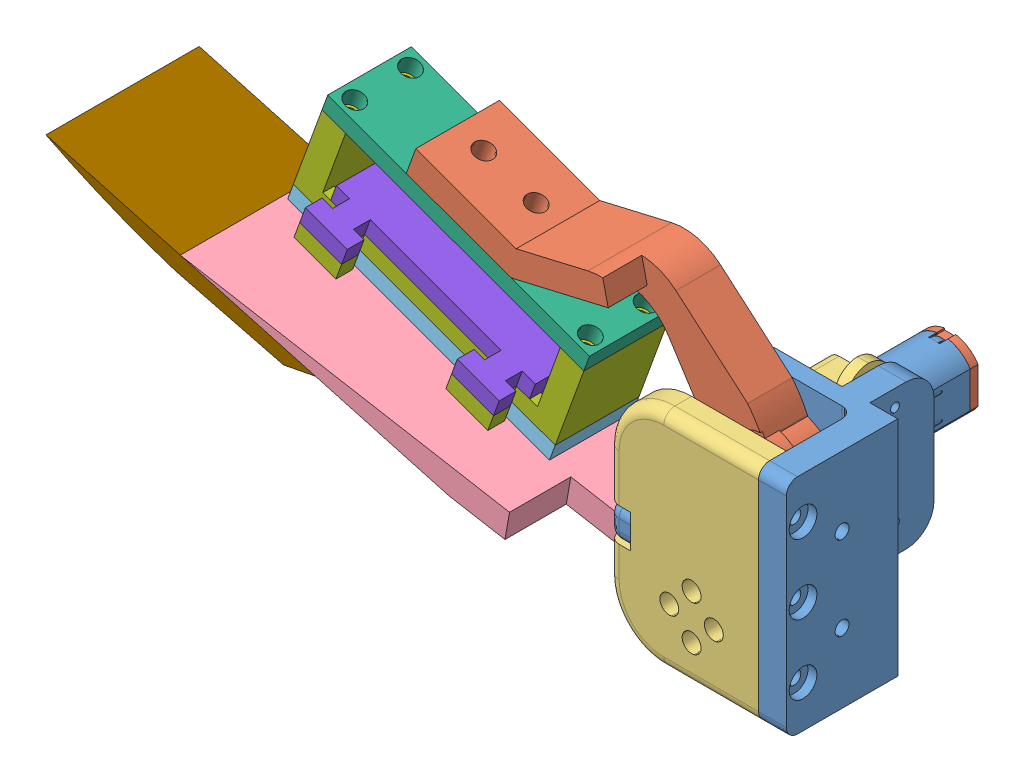
SolidWorks assembly Variable_Friction_Gripper, configuration 기본. Lengths in mm.
Overall size (127.24 66.06 52.21).
44 component instances, 41 part files, 39 mates.
Components (placement in the parent):
- vfg_part_1-1: vfg_part_1 [기본] at (-119.2345 24.8872 -4.25) size (32.32 40 31.5)
- vfg_part_2-1: vfg_part_2 [기본] at (-117.7345 24.8872 7.75) x (-0.34202 -0.939693 0) z (0 0 -1) size (27.85 68.5 15)
- vfg_part_3-1: vfg_part_3 [기본] at (-121.2345 16.8872 15.75) x (0 -1 0) z (0 0 -1) size (40 27 5)
- vfg_part_4-1: vfg_part_4 [기본] at (-119.7345 7.5872 0.75) x (-1 0 0) z (0 0 1) size (92.76 23.36 27.5)
- vfg_part_5-2: vfg_part_5 [기본] at (-168.6956 29.6012 7.25) x (0 0 -1) z (0.34202 0.939693 0) size (15 50 3)
- vfg_part_6-2: vfg_part_6 [기본] at (-162.5392 46.5157 7.25) x (0 0 -1) z (-0.34202 -0.939693 0) size (15 50 3)
- vfg_part_7-2: vfg_part_7 [기본] at (-163.5652 43.6966 7.25) x (0 0 -1) z (0.34202 0.939693 0) size (27 50 15)
- vfg_part_8-2: vfg_part_8 [기본] at (-167.6695 32.4203 7.25) x (0 0 -1) z (0.34202 0.939693 0) size (27 38 12)
- vfg_part_9-2: vfg_part_9 [기본] at (-186.9631 16.1459 8) x (0 0 -1) z (0.939824 -0.34166 0) size (27.5 5.12 50)
- Motor.IGS-1: Motor.IGS [기본] at (-117.7345 24.8872 -28.65) x (0 1 0) z (1 0 0) size (12.54 36.22 10.97)
  - Engrenagem reta1.stp.IGS-1: Engrenagem reta1.stp.IGS [기본] at (0 16.35 0) x (-0.429617 0 0.903011) z (0 1 0) size (2.8 2.81 1.26)
  - Engrenagem reta2.stp.IGS-1: Engrenagem reta2.stp.IGS [기본] at (0 16.35 3) x (-0.471104 0 -0.882078) z (0 1 0) size (3.6 3.61 0.52)
  - Engrenagem reta1_1.stp.IGS-1: Engrenagem reta1_1.stp.IGS [기본] at (0 16.85 3) x (-0.277142 0 -0.960829) z (0 1 0) size (1.92 1.93 1.51)
  - Engrenagem reta2_1.stp.IGS-1: Engrenagem reta2_1.stp.IGS [기본] at (3.0146 18.35 1.9633) x (0.883421 0 0.46858) z (0 -1 0) size (4.79 4.79 0.51)
  - Engrenagem reta1_2.stp.IGS-1: Engrenagem reta1_2.stp.IGS [기본] at (3.0146 18.35 1.9633) x (-0.985151 0 -0.171692) z (0 1 0) size (1.99 1.99 2.51)
  - Engrenagem reta2_2.stp.IGS-1: Engrenagem reta2_2.stp.IGS [기본] at (0 19.55 0) x (-0.718769 0 0.695249) z (0 1 0) size (5.59 5.59 0.52)
  - Engrenagem reta1_3.stp.IGS-1: Engrenagem reta1_3.stp.IGS [기본] at (0 20.05 0) x (-0.261212 0 0.965281) z (0 1 0) size (1.99 1.99 1.26)
  - Engrenagem reta2_3.stp.IGS-1: Engrenagem reta2_3.stp.IGS [기본] at (-3.0146 21.3 -1.9633) x (-0.981768 0 0.190082) z (0 -1 0) size (5.59 5.59 0.52)
  - Engrenagem reta1_4.stp.IGS-1: Engrenagem reta1_4.stp.IGS [기본] at (-3.0146 21.4 -1.9633) x (-0.349472 0 0.936947) z (0 1 0) size (1.99 1.99 1.76)
  - Engrenagem reta2_4.stp.IGS-1: Engrenagem reta2_4.stp.IGS [기본] at (0 23.45 0) x (0.007994 0 0.999968) z (0 -1 0) size (5.59 5.59 1.71)
  - Base.stp.IGS-1: Base.stp.IGS [기본] at origin size (11.84 5.21 10.01)
  - Rotor.stp.IGS-1: Rotor.stp.IGS [기본] at (0 18 0) x (-0.799859 0 0.600187) z (0.600187 0 0.799859) size (1.61 18.61 1.01)
  - Apoio Contato.stp.IGS-1: Apoio Contato.stp.IGS [기본] at (0 2.38 0) x (0.383204 0 -0.923664) z (0.923664 0 0.383204) size (1.84 0.15 1.83)
  - Contato.stp.IGS-1: Contato.stp.IGS [기본] at (0 5 0) x (-0.999891 0 -0.014787) z (0.014787 0 -0.999891) size (6.63 3.18 6.59)
  - Suporte Contato.stp.IGS-1: Suporte Contato.stp.IGS [기본] at (0 5.7 0) x (0.518288 0 -0.855206) z (0.855206 0 0.518288) size (2 3.01 1.81)
  - Im_X_E3s.stp.IGS-1: Im_X_E3s.stp.IGS [기본] at (0 5.7 0) x (0.999997 0 -0.002497) z (0.002497 0 0.999997) size (11.56 8.51 9.63)
  - Terminais.stp.IGS-1: Terminais.stp.IGS [기본] at (-3.1 2.45 0) x (-1 0 0) z (0 0 1) size (0.42 4.27 2.02)
  - Terminais.stp.IGS-2: Terminais.stp.IGS [기본] at (3.1 2.45 0) x (1 0 0) z (0 0 -1) size (0.42 4.27 2.02)
  - Escovas.stp.IGS-1: Escovas.stp.IGS [기본] at (0 1.5101 0) size (6.45 2.03 7.34)
  - Chapa Inferior.stp.IGS-1: Chapa Inferior.stp.IGS [기본] at (0 15.4 0) x (1 0 0) z (0 0 1) size (12.05 0.83 10.05)
  - Chapa Intermedi_X_E1ria.stp.IGS-1: Chapa Intermedi_X_E1ria.stp.IGS [기본] at (0 18.6 0) x (1 0 0) z (0 0 1) size (12.05 3.61 10.05)
  - Chapa Superior.stp.IGS-1: Chapa Superior.stp.IGS [기본] at (0 23.6 0) x (1 0 0) z (0 0 1) size (12.03 6.11 10.05)
  - Eixo Maior - Engrenagem.stp.IGS-1: Eixo Maior - Engrenagem.stp.IGS [기본] at (3.0146 24.3 1.9633) x (-1 0 -0.000674) z (-0.000674 0 1) size (0.93 8.82 0.92)
  - Eixo Menor - Engrenagem.stp.IGS-1: Eixo Menor - Engrenagem.stp.IGS [기본] at (-3.0146 18.7 -1.9633) x (0.670284 0 0.742105) z (-0.742105 0 0.670284) size (0.93 5.62 0.92)
  - Parafuso.stp.IGS-1: Parafuso.stp.IGS [기본] at (3.8014 14.4 -2.7994) x (-0.923373 0 -0.383904) z (0.383904 0 -0.923373) size (2.51 10.02 2.51)
  - Parafuso.stp.IGS-2: Parafuso.stp.IGS [기본] at (-3.8014 14.4 2.7994) x (0.953489 0 -0.301427) z (0.301427 0 0.953489) size (2.51 10.02 2.51)
  - Suporte Bobinas.stp.IGS-1: Suporte Bobinas.stp.IGS [기본] at (0 13.2 0) x (0.518288 0 -0.855206) z (0.855206 0 0.518288) size (8.04 8.51 7.87)
  - Eixo Menor - Engrenagem_1.stp.IGS-1: Eixo Menor - Engrenagem_1.stp.IGS [기본] at (0 15.5 3) x (0.739249 0 0.673433) z (-0.673433 0 0.739249) size (0.93 3.82 0.92)
  - Eixo - Encaixe D.stp.IGS-1: Eixo - Encaixe D.stp.IGS [기본] at (0 23.6 0) x (0.341465 0 -0.939895) z (0.939895 0 0.341465) size (4.53 16.01 3.04)
  - Carca_X_E7a.stp.IGS-1: Carca_X_E7a.stp.IGS [기본] at (-0.0269 14.9 -0.0079) x (1 0 0) z (0 0 1) size (12.47 14.46 10.02)
- polulu_mounting_hub-1: polulu_mounting_hub [기본] at (-117.7345 24.8872 -0.25) x (-0.34202 -0.939693 0) z (0 0 1) size (17.5 17.5 5)
- Pololu_bracket-1: Pololu_bracket [Domyślna] at (-112.7345 25.7492 -9.2359) x (0 1 0) z (-1 0 0) size (26.59 11.5 11.5)
- 8pc_623ZZ-1: 8pc_623ZZ [기본] at (-184.7567 32.2545 7.25) x (-0.294254 -0.808457 -0.509716) z (0.939693 -0.34202 0) size (10 10 32)
- 3mmx40mm_dowel_pin-1: 3mmx40mm_dowel_pin [기본] at (-150.9278 19.9417 7.25) x (-0.059751 -0.164165 -0.984622) z (-0.939693 0.34202 0) size (3 3 40)
Mates (geometry in assembly coordinates):
- 동심1: concentric aligned: cylinder of vfg_part_a-1 through (-102.7345 4.3872 12.75) axis (1 0 0) radius 2.5; cylinder of vfg_part_c-1 through (-107.7345 4.3872 12.75) axis (1 0 0) radius 0.8
- 동심2: concentric aligned: cylinder of vfg_part_a-1 through (-102.7345 29.3872 12.75) axis (1 0 0) radius 2.5; cylinder of vfg_part_c-1 through (-107.7345 29.3872 12.75) axis (1 0 0) radius 0.8
- 일치1: coincident anti-aligned: plane of vfg_part_a-1 through (-107.7345 36.8872 15.75) normal (-1 0 0); plane of vfg_part_c-1 through (-107.7345 36.8872 10.75) normal (1 0 0)
- 동심3: concentric aligned: cylinder of vfg_part_c-1 through (-123.7345 7.5872 15.75) axis (0 0 1) radius 1.7; cylinder of vfg_part_d-1 through (-123.7345 7.5872 10.75) axis (0 0 1) radius 1.25
- 동심4: concentric aligned: cylinder of vfg_part_c-1 through (-119.7345 3.5872 15.75) axis (0 0 1) radius 1.7; cylinder of vfg_part_d-1 through (-119.7345 3.5872 10.75) axis (0 0 1) radius 1.25
- 일치2: coincident anti-aligned: plane of vfg_part_c-1 through (-121.2345 16.8872 10.75) normal (0 0 -1); plane of vfg_part_d-1 through (-119.7345 7.5872 10.75) normal (0 0 1)
- 탄젠트1: tangent anti-aligned: plane of vfg_part_1-1 through (-112.7345 29.8872 -1.25) normal (-1 0 0); face of Motor.IGS-1/Carca_X_E7a.stp.IGS-1
- 동심5: concentric anti-aligned: cylinder of vfg_part_a-1 through (-112.7345 33.8872 -8.75) axis (-1 0 0) radius 0.8; cylinder of Pololu micro-1 through (-114.7345 33.8872 -8.75) axis (1 0 0) radius 1.5
- 동심6: concentric anti-aligned: cylinder of vfg_part_a-1 through (-112.7345 15.8872 -8.75) axis (-1 0 0) radius 0.8; cylinder of Pololu micro-1 through (-114.7345 15.8872 -8.75) axis (1 0 0) radius 1.5
- 일치3: coincident anti-aligned: plane of vfg_part_a-1 through (-112.7345 29.8872 -1.25) normal (-1 0 0); plane of Pololu micro-1 through (-112.7345 25.7492 -9.2359) normal (1 0 0)
- 탄젠트2: tangent: plane of assembly; face of Motor.IGS-1/Chapa Superior.stp.IGS-1; plane of Pololu_bracket-1 through (-122.7345 25.7492 -9.2359) normal (1 0 0)
- 탄젠트3: tangent: plane of assembly; face of Motor.IGS-1/Chapa Superior.stp.IGS-1; plane of Pololu_bracket-1 through (-122.7345 30.8872 -9.2359) normal (0 -1 0)
- 탄젠트4: tangent: plane of assembly; face of Motor.IGS-1/Chapa Intermedi_X_E1ria.stp.IGS-1; plane of Pololu_bracket-1 through (-122.7345 18.8872 -9.2359) normal (0 1 0)
- 탄젠트5: tangent anti-aligned: plane of vfg_part_1-1 through (-119.2345 24.8872 -4.25) normal (0 0 -1); edge_curve of Motor.IGS-1/Chapa Superior.stp.IGS-1
- 동심7: concentric aligned: cylinder of vfg_part_b-1 through (-117.7345 24.8872 -0.25) axis (0 0 1) radius 1.6
- 동심8: concentric anti-aligned: cylinder of vfg_part_b-1 through (-117.7345 24.8872 -20.7058) axis (0 0 1) radius 9; cylinder of gripper_mounting_hub-1 through (-117.7345 24.8872 4.75) axis (0 0 -1) radius 8.75
- 일치4: coincident anti-aligned: plane of vfg_part_b-1 through (-117.7345 24.8872 4.75) normal (0 0 -1); plane of gripper_mounting_hub-1 through (-117.7345 24.8872 4.75) normal (0 0 1)
- 동심9: concentric aligned: cylinder of vfg_part_b-1 through (-111.7675 22.7154 9.75) axis (0 0 1) radius 1.7; cylinder of gripper_mounting_hub-1 through (-111.7675 22.7154 4.75) axis (0 0 1) radius 1.25
- 거리1: distance = 1 mm anti-aligned: plane of vfg_part_a-1 through (-119.2345 24.8872 -1.25) normal (0 0 1); plane of gripper_mounting_hub-1 through (-117.7345 24.8872 -0.25) normal (0 0 -1)
- 동심10: concentric anti-aligned: cylinder of vfg_part_b-1 through (-165.5276 52.9243 7.25) axis (0.34202 0.939693 0) radius 1.7; cylinder of gripper_varstiff_3-1 through (-168.2637 45.4067 7.25) axis (-0.34202 -0.939693 0) radius 1.25
- 동심11: concentric anti-aligned: cylinder of vfg_part_b-1 through (-156.1306 49.5041 7.25) axis (0.34202 0.939693 0) radius 1.7; cylinder of gripper_varstiff_3-1 through (-158.8668 41.9865 7.25) axis (-0.34202 -0.939693 0) radius 1.25
- 일치5: coincident anti-aligned: plane of vfg_part_b-1 through (-153.1423 43.0955 -0.25) normal (-0.34202 -0.939693 0); plane of gripper_varstiff_3-1 through (-162.5392 46.5157 7.25) normal (0.34202 0.939693 0)
- 동심12: concentric anti-aligned: cylinder of vfg_part_7-2 through (-184.7083 51.3921 12.25) axis (0.34202 0.939693 0) radius 1.25; cylinder of gripper_varstiff_3-1 through (-184.7083 51.3921 12.25) axis (-0.34202 -0.939693 0) radius 1.7
- 동심13: concentric anti-aligned: cylinder of vfg_part_7-2 through (-184.7083 51.3921 2.25) axis (0.34202 0.939693 0) radius 1.25; cylinder of gripper_varstiff_3-1 through (-184.7083 51.3921 2.25) axis (-0.34202 -0.939693 0) radius 1.7
- 일치6: coincident anti-aligned: plane of vfg_part_7-2 through (-187.0576 52.2471 -6.251) normal (0.34202 0.939693 0); plane of gripper_varstiff_3-1 through (-163.5652 43.6966 7.25) normal (-0.34202 -0.939693 0)
- 일치7: coincident anti-aligned: plane of gripper_varstiff_1_roller-1 through (-167.6695 32.4203 7.25) normal (0.34202 0.939693 0); plane of gripper_varstiff_2_roller-1 through (-167.6695 32.4203 7.25) normal (-0.34202 -0.939693 0)
- 일치8: coincident aligned: plane of vfg_part_7-2 through (-185.0538 38.7477 -6.25) normal (0 0 -1); plane of gripper_varstiff_2_roller-1 through (-184.0277 41.5667 -6.25) normal (0 0 -1)
- 일치9: coincident aligned: plane of vfg_part_7-2 through (-185.0538 38.7477 -3.25) normal (-0.939693 0.34202 0); plane of gripper_varstiff_2_roller-1 through (-184.0277 41.5667 -3.25) normal (-0.939693 0.34202 0)
- 일치10: coincident anti-aligned: plane of vfg_part_7-2 through (-168.6956 29.6012 7.25) normal (-0.34202 -0.939693 0); plane of gripper_varstiff_silicone_roller-1 through (-168.6956 29.6012 7.25) normal (0.34202 0.939693 0)
- 일치11: coincident aligned: plane of vfg_part_7-2 through (-186.0315 55.0662 14.75) normal (-0.939693 0.34202 0); plane of gripper_varstiff_silicone_roller-1 through (-193.2139 35.3326 -0.25) normal (-0.939693 0.34202 0)
- 일치12: coincident aligned: plane of vfg_part_7-2 through (-186.0315 55.0662 -0.25) normal (0 0 -1); plane of gripper_varstiff_silicone_roller-1 through (-193.2139 35.3326 -0.25) normal (0 0 -1)
- 동심14: concentric anti-aligned: cylinder of gripper_varstiff_2_roller-1 through (-187.5758 33.2805 7.25) axis (-0.939693 0.34202 0) radius 1.5; cylinder of roller_pin-1 through (-188.5155 33.6225 7.25) axis (0.939693 -0.34202 0) radius 1.5
- 거리2: distance = 1 mm aligned: plane of roller_pin-1 through (-188.5155 33.6225 7.25) normal (-0.939693 0.34202 0); plane of gripper_varstiff_2_roller-1 through (-184.4976 41.7378 14.75) normal (-0.939693 0.34202 0)
- 동심15: concentric anti-aligned: cylinder of roller_bearing-1 through (-154.6865 21.3098 7.25) axis (-0.939693 0.34202 0) radius 5; cylinder of roller_pin-1 through (-188.5155 33.6225 7.25) axis (0.939693 -0.34202 0) radius 1.5
- 거리3: distance = 0.5 mm anti-aligned: plane of roller_bearing-1 through (-154.6865 21.3098 7.25) normal (0.939693 -0.34202 0); plane of gripper_varstiff_2_roller-1 through (-155.2427 18.3197 2.25) normal (-0.939693 0.34202 0)
- 일치13: coincident anti-aligned: plane of vfg_part_d-1 through (-205.4935 23.9431 -5.75) normal (-0.265752 -0.964041 0); plane of gripper_varstiff_tpu-1 through (-229.5945 30.5869 -5.75) normal (0.265752 0.964041 0)
- 일치14: coincident aligned: plane of vfg_part_d-1 through (-119.7345 7.5872 -5.75) normal (0 0 -1); plane of gripper_varstiff_tpu-1 through (-157.5333 173.4406 -5.75) normal (0 0 -1)
- 거리4: distance = 25 mm: line of vfg_part_d-1 through (-205.4935 23.9431 21.75) axis (0 0 -1); line of gripper_varstiff_tpu-1 through (-229.5945 30.5869 -5.75) axis (0 0 1)
- 각도1: planar angle = 0.174533 rad anti-aligned: plane of gripper_varstiff_silicone_roller-1 through (-169.7216 26.7821 7.25) normal (-0.34202 -0.939693 0); plane of vfg_part_d-1 through (-205.4935 23.9431 10.75) normal (0.173648 0.984808 0)
